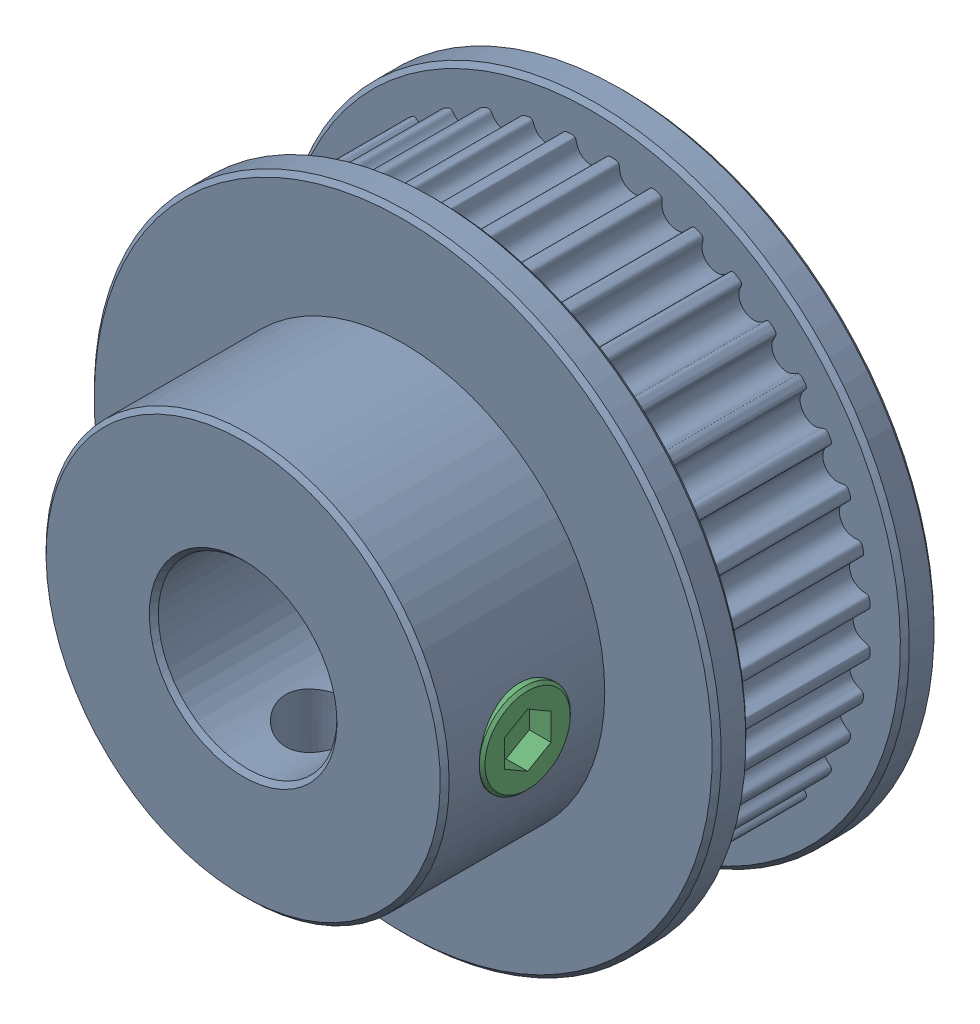
SolidWorks assembly GT2 40T 8 Bore v2, configuration ﾃﾞﾌｫﾙﾄ. Lengths in mm.
Overall size (28 28 17.05).
3 component instances, 3 part files, 0 mates.
Components (placement in the parent):
- Pulley-1: Pulley [ﾃﾞﾌｫﾙﾄ] at origin size (28 28 17.05)
- Screw v1-1: Screw v1 [ﾃﾞﾌｫﾙﾄ] at (-0.0003 1.0749 20.025) size (4.06 2.49 4.06)
- Screw v1 (1)-1: Screw v1 (1) [ﾃﾞﾌｫﾙﾄ] at (-1.0753 -7.5501 12.475) x (0 0 1) z (0 -1 0) size (4.06 2.49 4.06)
